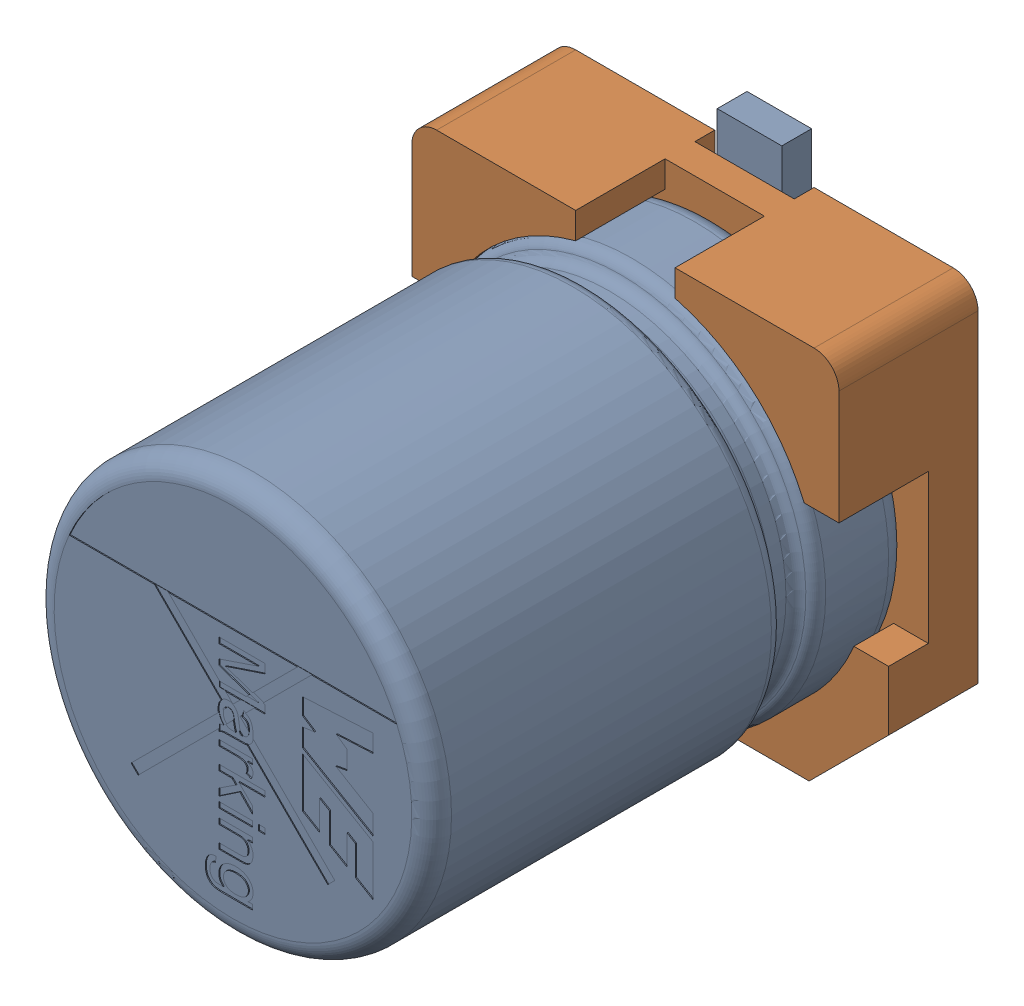
SolidWorks assembly 4x5.5x1, configuration Default. Lengths in mm.
Overall size (4.3 5 5.5).
2 component instances, 2 part files, 0 mates.
Components (placement in the parent):
- capicitor_4x5.5x1-1: capicitor_4x5.5x1 [Default] at (0 0 0.5) x (0 -1 0) z (0 0 1) size (5 4 5.5)
- Base___X2__03A6__X0__4Capacitor-1: Base___X2__03A6__X0__4Capacitor [Default] at origin size (4.3 4.3 1.46)
